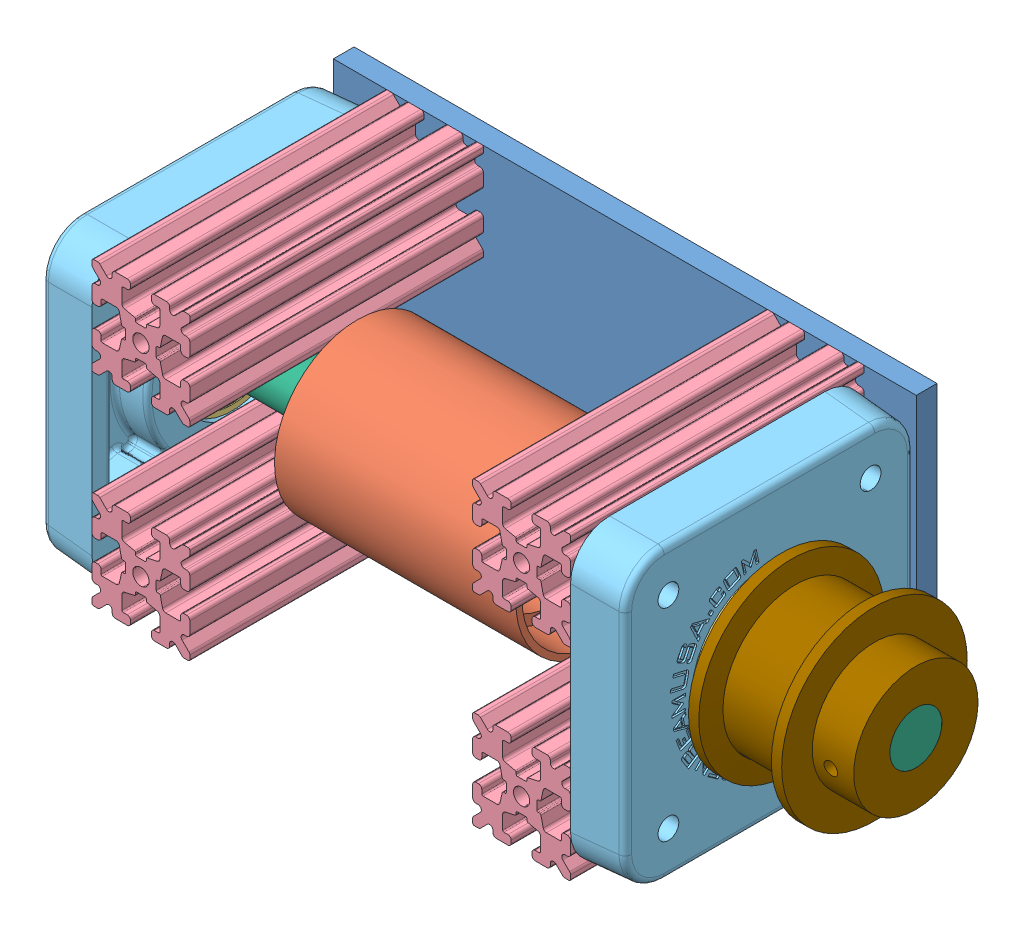
SolidWorks assembly Assembly_Film_Feeder, configuration Default. Lengths in mm.
Overall size (122.61 46 48.18).
15 component instances, 9 part files, 37 mates.
Components (placement in the parent):
- Base_Plate-1: Base_Plate [Default] at origin size (89.35 46 3.17)
- Film_Sprocket-1: Film_Sprocket [Default] at (-18.5 0.006 25.675) x (0 0.938705 -0.344721) z (1 0 0) size (25.4 25.4 37)
- Bearing_ID6mm_OD22mm-1: Bearing_ID6mm_OD22mm [5972K501] at (-41.1755 0.006 25.675) x (0 1 0) z (1 0 0) size (22 22 7)
- Bearing_ID6mm_OD22mm-2: Bearing_ID6mm_OD22mm [5972K501] at (41.1755 0.006 25.675) x (0 1 0) z (1 0 0) size (22 22 7)
- Beam_Riser-1: Beam_Riser [Default] at (-29.1755 15.5 25.675) size (15 15 45)
- Plate_608_to_NEMA17-1: Plate_608_to_NEMA17 [Default] at (-44.6755 0.006 25.675) x (0 -1 0) z (0 0 1) size (45 8 45)
- Beam_Riser-2: Beam_Riser [Default] at (29.1755 15.5 25.675) size (15 15 45)
- Beam_Riser-3: Beam_Riser [Default] at (-29.1755 -15.5 25.675) x (1 0 0) z (0 0 -1) size (15 15 45)
- Feeder_Support_Rod-1: Feeder_Support_Rod [Default] at (-55.4755 0.006 25.675) x (0 -0.122012 0.992529) z (0 0.992529 0.122012) size (8 122.59 8)
- Shaft_Collar-1: Shaft_Collar [9506T4] at (-50.9755 0.006 25.675) x (0 0.122012 -0.992529) z (-1 0 0) size (18 18.24 9.05)
- Washer_M8-1: Washer_M8 [92334A116] at (-44.6755 0.006 25.675) x (0 -0.122012 0.992529) z (-1 0 0) size (16 16 1.8)
- Beam_Riser-4: Beam_Riser [Default] at (29.1755 -15.5 25.675) x (1 0 0) z (0 0 -1) size (15 15 45)
- Plate_608_to_NEMA17-2: Plate_608_to_NEMA17 [Default] at (44.6755 0.006 25.675) x (0 1 0) z (0 0 1) size (45 8 45)
- Washer_M8-2: Washer_M8 [92334A116] at (46.4755 0.006 25.675) x (0 1 0) z (-1 0 0) size (16 16 1.8)
- Timing_Pulley_14T-1: Timing_Pulley_14T [Default] at (53.6192 0.006 25.675) x (0 -0.122012 0.992529) z (1 0 0) size (28.45 28.45 20.64)
Mates (geometry in assembly coordinates):
- Coincident1: coordinate: point of Base_Plate-1; point of assembly
- Coincident6: coincident anti-aligned: plane of Base_Plate-1 through (0 0 3.175) normal (0 0 1); plane of Beam_Riser-1 through (-29.1755 15.5 3.175) normal (0 0 -1)
- Parallel1: parallel aligned: plane of Base_Plate-1 through (-44.6745 23 3.175) normal (0 1 0); plane of Beam_Riser-1 through (-36.6755 23 48.175) normal (0 1 0)
- Width1: width anti-aligned: plane of Beam_Riser-1 through (-36.6755 13.9 3.175) normal (0 1 0); plane of Beam_Riser-1 through (-36.6755 17.1 3.175) normal (0 -1 0); cylinder of Plate_608_to_NEMA17-1 through (-36.6755 15.5 41.169) axis (-1 0 0) radius 1.6
- Width2: width anti-aligned: plane of Beam_Riser-1 through (-36.6755 17.1 3.175) normal (0 -1 0); plane of Beam_Riser-1 through (-36.6755 13.9 3.175) normal (0 1 0); cylinder of Plate_608_to_NEMA17-1 through (-36.6755 15.5 10.181) axis (-1 0 0) radius 1.6
- Coincident8: coincident: plane of Base_Plate-1 through (0 0 3.175) normal (0 0 1); line of Plate_608_to_NEMA17-1 through (-36.6755 -16.5022 3.175) axis (0 1 0)
- Coincident9: coincident anti-aligned: plane of Beam_Riser-1 through (-36.6755 8 48.175) normal (-1 0 0); plane of Plate_608_to_NEMA17-1 through (-36.6755 0.006 25.675) normal (1 0 0)
- Concentric4: concentric anti-aligned: cylinder of Bearing_ID6mm_OD22mm-1 through (-37.6755 0.006 25.675) axis (1 0 0) radius 11; cylinder of Plate_608_to_NEMA17-1 through (-36.6755 0.006 25.675) axis (-1 0 0) radius 11
- Coincident10: coincident anti-aligned: plane of Bearing_ID6mm_OD22mm-1 through (-37.6755 0.006 36.325) normal (1 0 0); plane of Plate_608_to_NEMA17-1 through (-37.6755 0.006 25.675) normal (-1 0 0)
- Parallel3: parallel aligned: plane of Bearing_ID6mm_OD22mm-1; plane of Plate_608_to_NEMA17-1 through (-44.6755 0.006 25.675) normal (0 0 1)
- Concentric5: concentric anti-aligned: cylinder of Bearing_ID6mm_OD22mm-1 through (-37.6755 0.006 25.675) axis (1 0 0) radius 4; cylinder of Feeder_Support_Rod-1 through (67.1103 0.006 25.675) axis (-1 0 0) radius 4
- Concentric6: concentric anti-aligned: cylinder of Feeder_Support_Rod-1 through (67.1103 0.006 25.675) axis (-1 0 0) radius 4; cylinder of Shaft_Collar-1 through (-55.4755 0.006 25.675) axis (1 0 0) radius 4
- Coincident12: coincident aligned: plane of Feeder_Support_Rod-1 through (-55.4755 0.006 25.675) normal (-1 0 0); plane of Shaft_Collar-1 through (-55.4755 0.006 25.675) normal (-1 0 0)
- Coincident13: coincident anti-aligned: plane of Feeder_Support_Rod-1 through (-55.4755 0.006 25.675) normal (0 0.992529 0.122012); plane of Shaft_Collar-1
- Concentric7: concentric anti-aligned: cylinder of Feeder_Support_Rod-1 through (67.1103 0.006 25.675) axis (-1 0 0) radius 4; cylinder of Washer_M8-1 through (-46.4755 0.006 25.675) axis (1 0 0) radius 4.2
- Coincident14: coincident anti-aligned: plane of Shaft_Collar-1 through (-46.4755 0.006 25.675) normal (1 0 0); plane of Washer_M8-1 through (-46.4755 0.006 25.675) normal (-1 0 0)
- Coincident15: coincident anti-aligned: plane of Shaft_Collar-1; plane of Washer_M8-1
- Coincident16: coincident anti-aligned: plane of Bearing_ID6mm_OD22mm-1 through (-44.6755 0.006 30.025) normal (-1 0 0); plane of Washer_M8-1 through (-44.6755 0.006 25.675) normal (1 0 0)
- Concentric8: concentric aligned: cylinder of Film_Sprocket-1 through (18.5 0.006 25.675) axis (-1 0 0) radius 10.1745; cylinder of Feeder_Support_Rod-1 through (67.1103 0.006 25.675) axis (-1 0 0) radius 4
- Coincident17: coincident anti-aligned: plane of Base_Plate-1 through (0 0 3.175) normal (0 0 1); plane of Beam_Riser-2 through (29.1755 15.5 3.175) normal (0 0 -1)
- Parallel4: parallel aligned: plane of Base_Plate-1 through (-44.6745 23 3.175) normal (0 1 0); plane of Beam_Riser-2 through (21.6755 23 48.175) normal (0 1 0)
- Width3: width anti-aligned: plane of Beam_Riser-2 through (36.6755 13.9 3.175) normal (0 1 0); plane of Beam_Riser-2 through (36.6755 17.1 3.175) normal (0 -1 0); cylinder of Plate_608_to_NEMA17-2 through (36.6755 15.5 10.181) axis (1 0 0) radius 1.6
- Width4: width anti-aligned: plane of Beam_Riser-2 through (36.6755 17.1 3.175) normal (0 -1 0); plane of Beam_Riser-2 through (36.6755 13.9 3.175) normal (0 1 0); cylinder of Plate_608_to_NEMA17-2 through (36.6755 15.5 41.169) axis (1 0 0) radius 1.6
- Coincident19: coincident: plane of Base_Plate-1 through (0 0 3.175) normal (0 0 1); line of Plate_608_to_NEMA17-2 through (36.6755 16.5142 3.175) axis (0 -1 0)
- Coincident20: coincident anti-aligned: plane of Beam_Riser-2 through (36.6755 8 48.175) normal (1 0 0); plane of Plate_608_to_NEMA17-2 through (36.6755 0.006 25.675) normal (-1 0 0)
- Concentric10: concentric aligned: cylinder of Bearing_ID6mm_OD22mm-2 through (44.6755 0.006 25.675) axis (1 0 0) radius 11; cylinder of Plate_608_to_NEMA17-2 through (36.6755 0.006 25.675) axis (1 0 0) radius 11
- Coincident21: coincident anti-aligned: plane of Bearing_ID6mm_OD22mm-2 through (37.6755 0.006 36.325) normal (-1 0 0); plane of Plate_608_to_NEMA17-2 through (37.6755 0.006 25.675) normal (1 0 0)
- Parallel5: parallel aligned: plane of Bearing_ID6mm_OD22mm-2; plane of assembly through (0 0 0) normal (0 0 1)
- Concentric12: concentric anti-aligned: cylinder of Feeder_Support_Rod-1 through (67.1103 0.006 25.675) axis (-1 0 0) radius 4; cylinder of Washer_M8-2 through (44.6755 0.006 25.675) axis (1 0 0) radius 4.2
- Coincident24: coincident anti-aligned: plane of Bearing_ID6mm_OD22mm-2 through (44.6755 0.006 32.5157) normal (1 0 0); plane of Washer_M8-2 through (44.6755 0.006 25.675) normal (-1 0 0)
- Coincident25: coincident anti-aligned: plane of Bearing_ID6mm_OD22mm-2; plane of Washer_M8-2
- Concentric13: concentric aligned: cylinder of Feeder_Support_Rod-1 through (67.1103 0.006 25.675) axis (-1 0 0) radius 4; cylinder of Timing_Pulley_14T-1 through (46.4755 0.006 25.675) axis (-1 0 0) radius 4
- Coincident26: coincident anti-aligned: plane of Washer_M8-2 through (46.4755 0.006 25.675) normal (1 0 0); plane of Timing_Pulley_14T-1 through (46.4755 0.006 25.675) normal (-1 0 0)
- Coincident29: coincident aligned: plane of Shaft_Collar-1; plane of Timing_Pulley_14T-1
- Width5: width anti-aligned: plane of Plate_608_to_NEMA17-2 through (36.6755 0.006 25.675) normal (-1 0 0); plane of Plate_608_to_NEMA17-1 through (-36.6755 0.006 25.675) normal (1 0 0); plane of Film_Sprocket-1 through (18.5 0.006 25.675) normal (1 0 0); plane of Film_Sprocket-1 through (-18.5 0.006 25.675) normal (-1 0 0)
- Concentric14: concentric aligned: cylinder of Beam_Riser-1 through (-29.1755 15.5 48.175) axis (0 0 -1) radius 1.25; cylinder of Base_Plate-1 through (-29.1755 15.5 0) axis (0 0 -1) radius 1.7
- Concentric15: concentric aligned: cylinder of Beam_Riser-2 through (29.1755 15.5 48.175) axis (0 0 -1) radius 1.25; cylinder of Base_Plate-1 through (29.1755 15.5 0) axis (0 0 -1) radius 1.7
